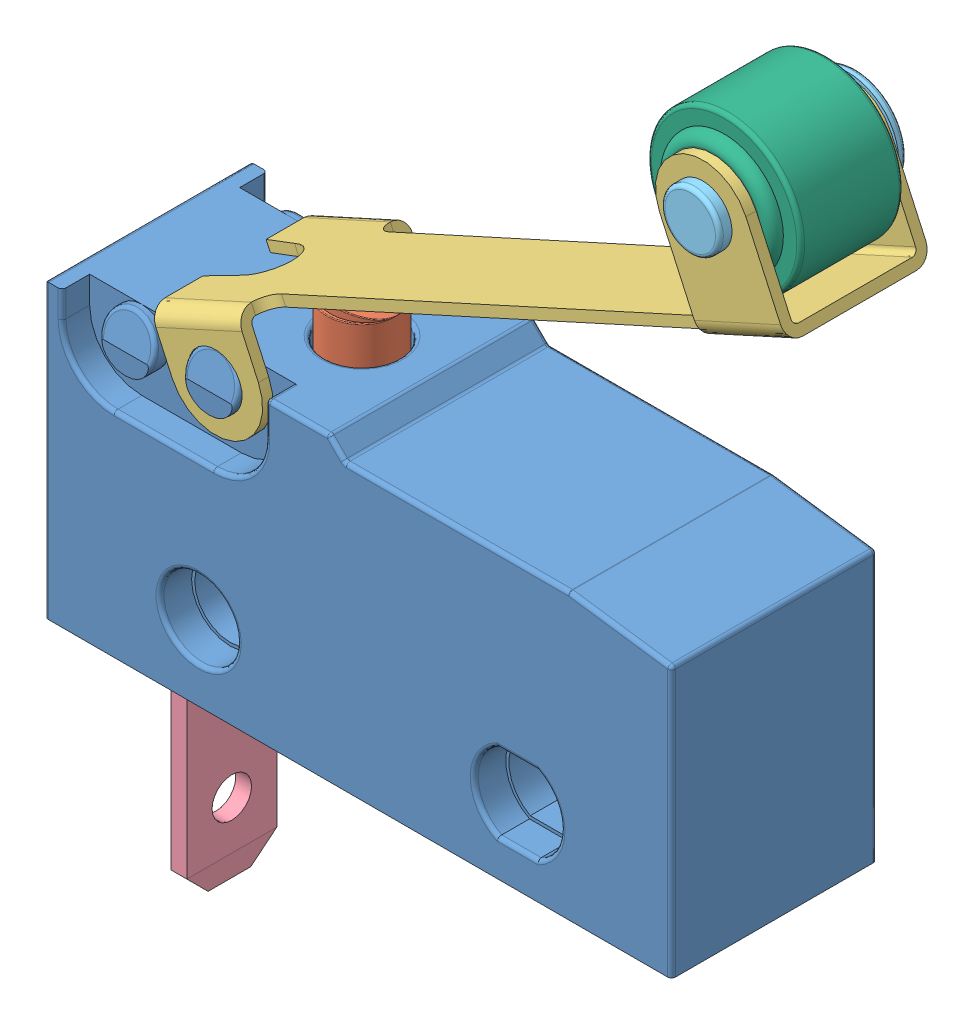
SolidWorks assembly Switch, configuration Default. Lengths in mm.
Overall size (23.77 31.42 6.5).
8 component instances, 6 part files, 18 mates.
Components (placement in the parent):
- corpo-1: corpo [Default] at (1.1317 -3.5508 1.8152) size (19.85 9.5 6.5) (hidden)
- botao-1: botao [Default] at (-1.9933 4.4492 1.8152) size (2.28 2.9 2.2) (hidden)
- haste-1: haste [Default] at (3.8671 10.3945 1.8152) x (-0.910275 -0.414005 0) z (0 0 -1) size (21.6 7.58 5.4) (hidden)
- pinsw-1: pinsw [Default] at (-6.3683 -11.0508 1.8152) x (0 0 -1) z (1 0 0) size (2.85 8.5 0.5) (hidden)
- pino_haste-1: pino_haste [Default] at (11.0958 16.9642 1.8152) x (-0.999999 -0.001388 0) z (0 0 -1) size (3.2 3.2 5.25) (hidden)
- roda-1: roda [Default] at (11.0958 16.9642 1.8152) x (0.78164 -0.62373 0) z (0 0 -1) size (4.85 4.85 3.95) (hidden)
- pinsw-3: pinsw [Default] at (1.1317 -11.0508 1.8152) x (0 0 -1) z (1 0 0) size (2.85 8.5 0.5) (hidden)
- pinsw-5: pinsw [Default] at (8.6317 -11.0508 1.8152) x (0 0 -1) z (1 0 0) size (2.85 8.5 0.5) (hidden)
Mates (geometry in assembly coordinates):
- Concentric1: concentric anti-aligned: cylinder of corpo-1 through (-1.9933 2.9492 1.8152) axis (0 1 0) radius 1.175; cylinder of botao-1 through (-1.9933 7.0492 1.8152) axis (0 -1 0) radius 1.1
- Coincident2: coincident anti-aligned: plane of corpo-1 through (-6.1183 -2.5508 3.2402) normal (-1 0 0); plane of pinsw-1 through (-6.1183 -2.5508 0.3902) normal (1 0 0)
- Coincident3: coincident anti-aligned: plane of corpo-1 through (-6.6183 -2.5508 0.3902) normal (0 0 1); plane of pinsw-1 through (-6.1183 -11.0508 0.3902) normal (0 0 -1)
- Coincident4: coincident anti-aligned: plane of corpo-1 through (-6.6183 -2.5508 0.3902) normal (0 -1 0); plane of pinsw-1 through (-6.1183 -2.5508 3.2402) normal (0 1 0)
- Coincident5: coincident anti-aligned: plane of corpo-1 through (1.3817 -2.5508 3.2402) normal (-1 0 0); plane of pinsw-3 through (1.3817 -2.5508 0.3902) normal (1 0 0)
- Coincident6: coincident anti-aligned: plane of corpo-1 through (0.8817 -2.5508 0.3902) normal (0 0 1); plane of pinsw-3 through (1.3817 -11.0508 0.3902) normal (0 0 -1)
- Coincident7: coincident anti-aligned: plane of corpo-1 through (0.8817 -2.5508 0.3902) normal (0 -1 0); plane of pinsw-3 through (1.3817 -2.5508 3.2402) normal (0 1 0)
- Coincident8: coincident anti-aligned: plane of corpo-1 through (8.8817 -2.5508 3.2402) normal (-1 0 0); plane of pinsw-5 through (8.8817 -2.5508 0.3902) normal (1 0 0)
- Coincident9: coincident anti-aligned: plane of corpo-1 through (8.3817 -2.5508 0.3902) normal (0 0 1); plane of pinsw-5 through (8.8817 -11.0508 0.3902) normal (0 0 -1)
- Coincident10: coincident anti-aligned: plane of corpo-1 through (8.3817 -2.5508 0.3902) normal (0 -1 0); plane of pinsw-5 through (8.8817 -2.5508 3.2402) normal (0 1 0)
- Coincident11: coincident anti-aligned: circle of haste-1; cylinder of roda-1 through (11.0958 16.9642 3.7902) axis (0 0 -1) radius 0.75
- Coincident12: coincident anti-aligned: plane of haste-1 through (11.8402 18.9506 -0.1598) normal (0 0 1); plane of roda-1 through (11.0958 16.9642 -0.1598) normal (0 0 -1)
- Concentric2: concentric anti-aligned: cylinder of pino_haste-1 through (11.0958 16.9642 -0.4848) axis (0 0 1) radius 0.75; cylinder of roda-1 through (11.0958 16.9642 3.7902) axis (0 0 -1) radius 0.75
- Coincident13: coincident anti-aligned: plane of haste-1 through (13.6308 15.0136 -0.4848) normal (0 0 -1); plane of pino_haste-1 through (11.0958 16.9642 -0.4848) normal (0 0 1)
- Concentric3: concentric anti-aligned: cylinder of haste-1 through (-3.9412 5.0992 4.5152) axis (0 0 -1) radius 0.85; cylinder of corpo-1 through (-3.9412 5.0992 -1.0848) axis (0 0 1) radius 0.85
- Coincident14: coincident anti-aligned: plane of corpo-1 through (-6.5933 4.8492 -0.5598) normal (0 0 -1); plane of haste-1 through (-1.9548 4.3548 -0.5598) normal (0 0 1)
- Tangent1: tangent anti-aligned: cylinder of botao-1 through (-1.9933 4.7492 0.7152) axis (0 0 1) radius 2.55; plane of haste-1 through (10.807 13.3723 3.7652) normal (0.414005 -0.910275 0)
- LimitAngle1: limit planar angle = 1.143947 rad aligned: plane of corpo-1 through (-8.7933 5.6992 5.0652) normal (0 1 0); plane of haste-1 through (13.6308 15.0136 4.1152) normal (0.910275 0.414005 0)
